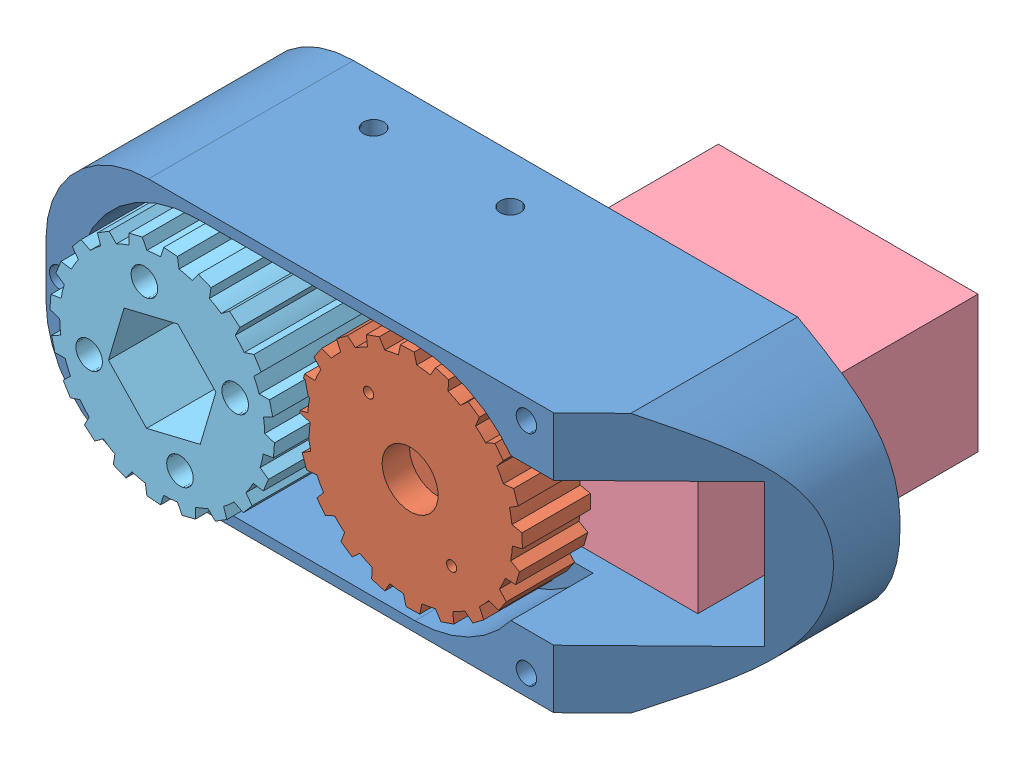
SolidWorks assembly neck gearbox assm, configuration Default. Lengths in mm.
Overall size (96.66 46 60).
6 component instances, 6 part files, 11 mates.
Components (placement in the parent):
- neckrot-1: neckrot [Default] at origin size (96.66 38 30)
- neckrot_top-1: neckrot_top [Default] at (0 0 30) size (96.66 38 30) (hidden)
- neckrotlarge-2: neckrotlarge [Default] at (3.0832 -0.1351 29.8) x (0.607956 -0.793971 0) z (0 0 -1) size (32.81 32.81 10)
- bearing-1: bearing [Default] at (-28 0 18) x (-0.313744 -0.949508 0) z (0 0 -1) size (22 22 7)
- servo standard-1: servo standard [Default] at (31.3832 -0.1351 -4.0202) x (0 0 -1) z (-1 0 0) size (49 20 52)
- neckrotlarge mount-1: neckrotlarge mount [Default] at (-28 0 18) x (0.971584 0.236697 0) z (0 0 1) size (32.81 32.81 17)
Mates (geometry in assembly coordinates):
- Coincident1: coincident anti-aligned: plane of bearing-1 through (-28 0 11) normal (0 0 -1); plane of neckrot-1 through (-28 0 11) normal (0 0 1)
- Concentric1: concentric anti-aligned: circle of neckrot-1; circle of bearing-1
- Concentric3: concentric anti-aligned: circle of servo standard-1; circle of neckrot-1
- Coincident5: coincident: plane of neckrot-1 through (39.9 10.4457 2) normal (0 0 1); line of servo standard-1
- Parallel1: parallel anti-aligned: plane of neckrot-1 through (-7.8 10.4457 30) normal (0 -1 0); plane of servo standard-1 through (-6.6168 10.0893 16) normal (0 1 0)
- Concentric6: concentric aligned: circle of neckrotlarge-2; circle of servo standard-1
- Coincident7: coincident anti-aligned: plane of neckrotlarge-2 through (3.0832 -0.1351 19.8) normal (0 0 -1); plane of servo standard-1 through (3.0832 -0.1351 19.8) normal (0 0 1)
- Coincident10: coincident aligned: circle of neckrot_top-1; circle of neckrot-1
- Coincident11: coincident aligned: circle of neckrot-1; circle of neckrot_top-1
- Coincident12: coincident anti-aligned: plane of neckrotlarge mount-1 through (-28 0 18) normal (0 0 -1); plane of neckrot-1 through (-28 0 18) normal (0 0 1)
- Concentric7: concentric aligned: circle of bearing-1; circle of neckrotlarge mount-1
